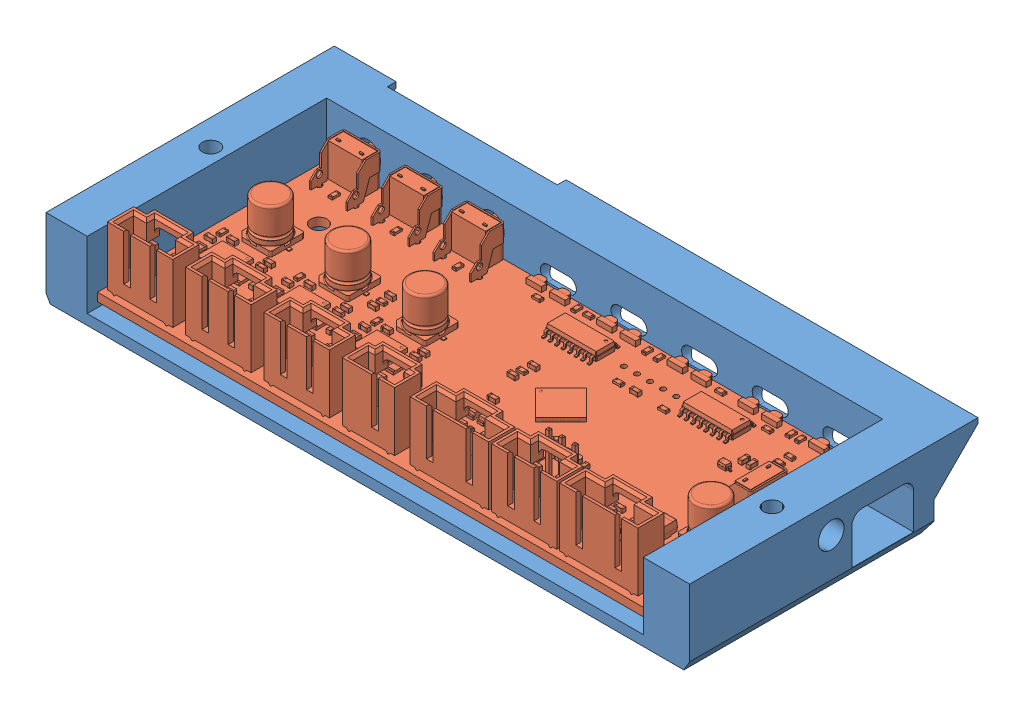
SolidWorks assembly MMU2 Ele Assembly, configuration Default. Lengths in mm.
Overall size (125 17.41 56).
2 component instances, 2 part files, 3 mates.
Components (placement in the parent):
- mmu2-ele-cover(M1)-1: mmu2-ele-cover(M1) [Default] at (0.0295 94.3969 96.7837) x (1 0 0) z (0 -1 0) size (125 56 15)
- MM-control-1: MM-control [Default] at (86.0295 60.3969 85.7837) x (-1 0 0) z (0 1 0) size (107.3 50.26 15.75)
Mates (geometry in assembly coordinates):
- Concentric1: concentric: circle of mmu2-ele-cover(M1)-1; circle of MM-control-1
- Concentric2: concentric: cylinder of mmu2-ele-cover(M1)-1 through (30.0295 65.8969 118.7837) axis (0 -1 0) radius 1.65; cylinder of MM-control-1 through (30.0295 81.245 118.7837) axis (0 1 0) radius 1.6
- Coincident1: coincident anti-aligned: plane of mmu2-ele-cover(M1)-1 through (78.0295 60.3969 104.7837) normal (0 1 0); plane of MM-control-1 through (86.0295 60.3969 85.7837) normal (0 -1 0)
